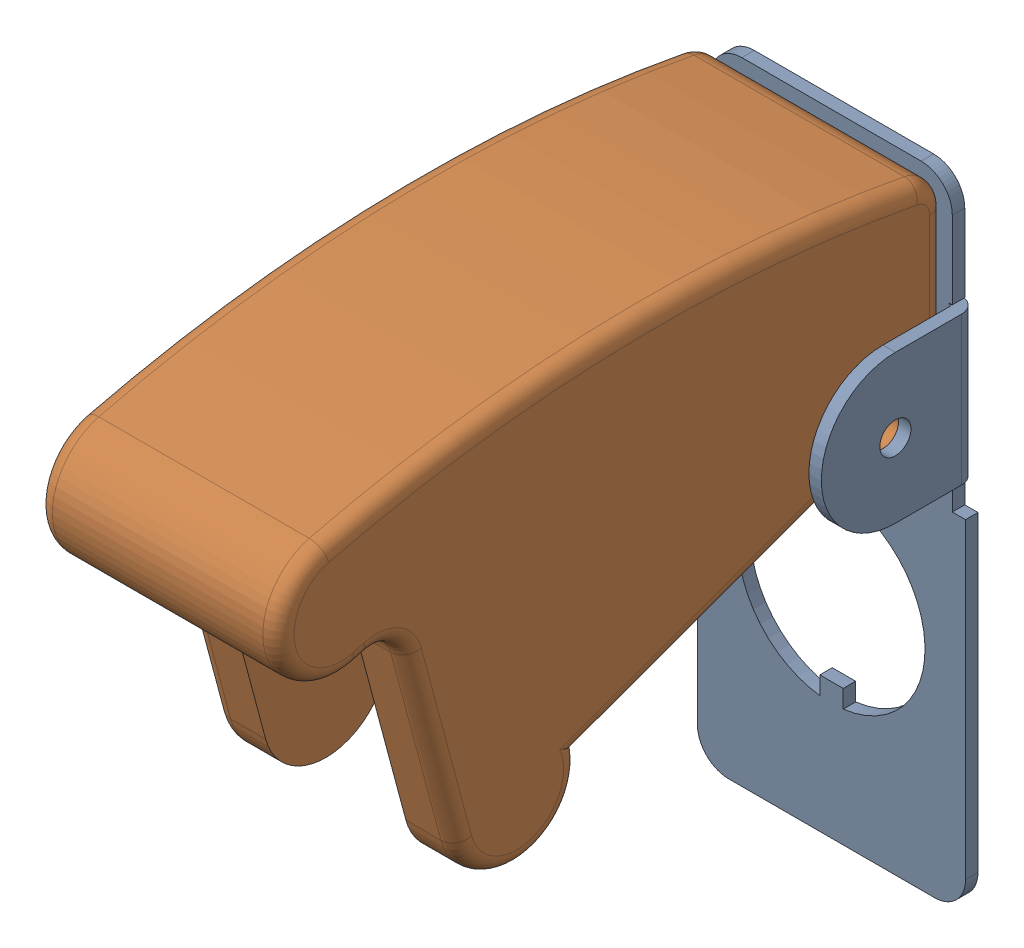
SolidWorks assembly Toggle Switch Guard Red v4, configuration Default. Lengths in mm.
Overall size (17.2 52.92 48.29).
2 component instances, 2 part files, 0 mates.
Components (placement in the parent):
- BasicToggleBasePlate-1: BasicToggleBasePlate [Default] at (67.6 15.075 4.2926) size (17.2 40.5 10)
- BasicToggle switch cover-1: BasicToggle switch cover [Default] at (83.95 45.9841 4.1633) x (0 -0.34202 0.939693) z (-1 0 0) size (41.56 27.01 15.51)
